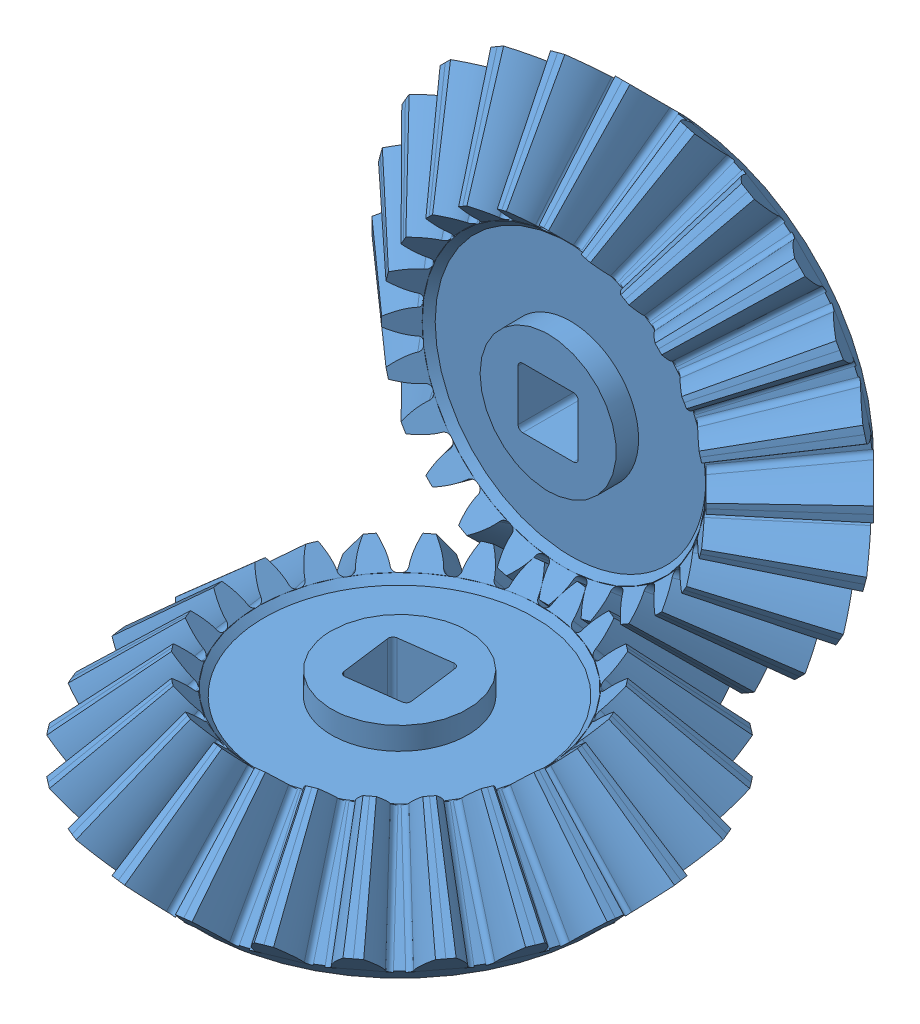
SolidWorks assembly BEVEL-ASSY, configuration Default. Lengths in mm.
Overall size (30.18 32.22 33.86).
2 component instances, 1 part files, 0 mates.
Components (placement in the parent):
- Bevel-Gear-1: Bevel-Gear [Default] at (0 -12.7043 20.5659) x (0.991445 0 -0.130526) z (0 -1 0) size (26.9 26.9 11.04)
- Bevel-Gear-2: Bevel-Gear [Default] at (0 0 7.8616) x (-1 0 0) z (0 0 -1) size (26.9 26.9 11.04)
